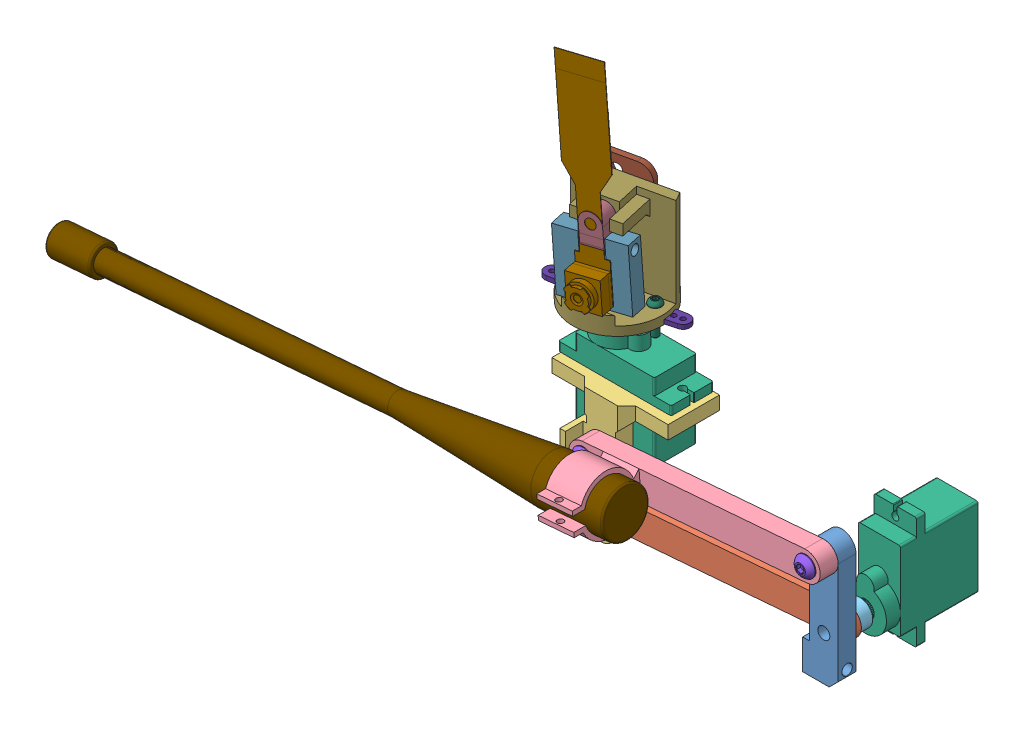
SolidWorks assembly 4barlift, configuration Default. Lengths in mm.
Overall size (209.39 119.55 61.9).
25 component instances, 18 part files, 60 mates.
Components (placement in the parent):
- UprightLinkage-3: UprightLinkage [Default] at (10.2426 1.5539 4.1287) size (10.06 32.9 5.08)
- LongLinkage_servointerface-3: LongLinkage_servointerface [Default] at (543.0293 904.0345 -372.7762) x (-0.080787 0.996731 0) z (0 0 1) size (8.13 71.63 5.08)
- TopLinkage-1: TopLinkage [Default] at (-53.0498 -3.5761 4.1287) size (33.02 35.81 22.23)
- LongLinkage-4: LongLinkage [Default] at (543.0293 923.0845 -362.6162) x (-0.080787 0.996731 0) z (0 0 1) size (15.87 71.63 24.1)
- servo horn 1 v2.step-1: servo horn 1 v2.step [Default] at (10.2426 1.5539 1.4047) x (0.080787 -0.996731 0) z (-0.996731 -0.080787 0) size (7.2 3.7 21.2)
- Towerpro Micro Servo 9g (1)-1: Towerpro Micro Servo 9g (1) [Varsayılan] at (10.2426 6.8039 -28.5953) x (-1 0 0) z (0 1 0) size (12 30 32)
- Towerpro Micro Servo 9g (1)-2: Towerpro Micro Servo 9g (1) [Varsayılan] at (-54.2298 13.1739 -1.8713) x (0 0 -1) z (1 0 0) size (12 30 32)
- 91028A411_JIS Hex Nut-1: 91028A411_JIS Hex Nut [91028A411] at (-53.0498 -3.5761 7.3607) x (0.882673 -0.469988 0) z (-0.469988 -0.882673 0) size (5.5 2.81 6.35)
- 91028A411_JIS Hex Nut-2: 91028A411_JIS Hex Nut [91028A411] at (10.2426 20.6039 5.9767) x (0.990104 -0.140335 0) z (0.140335 0.990104 0) size (5.5 2.81 6.35)
- 94500A223_316 Stainless Steel Button Head Hex Drive Screws-1: 94500A223_316 Stainless Steel Button Head Hex Drive Screws [94500A223] at (-53.0498 -3.5761 -2.6013) x (-0.923728 -0.383049 0) z (0 0 -1) size (5.7 5.7 11.96)
- 94500A223_316 Stainless Steel Button Head Hex Drive Screws-2: 94500A223_316 Stainless Steel Button Head Hex Drive Screws [94500A223] at (-53.0498 15.4739 15.9387) x (0.957545 0.288284 0) z (0 0 1) size (5.7 5.7 11.96)
- 94500A223_316 Stainless Steel Button Head Hex Drive Screws-3: 94500A223_316 Stainless Steel Button Head Hex Drive Screws [94500A223] at (10.2426 20.6039 15.9387) size (5.7 5.7 11.96)
- 91028A411_JIS Hex Nut-3: 91028A411_JIS Hex Nut [91028A411] at (-53.0498 15.4739 5.9767) x (-0.296491 0.955036 0) z (-0.955036 -0.296491 0) size (5.5 2.81 6.35)
- B006604.step-1: B006604.step [Default] at (-56.3424 53.482 7.8836) x (0.973205 0.071085 -0.218674) z (0.071693 -0.997413 -0.005162) size (12 6.7 59)
- hdmi_to_csi.step-1: hdmi_to_csi.step [Default] at (-63.9638 60.2486 -7.5722) x (-0.000051 -1 0.000012) z (0.219229 0 0.975673) size (29.21 18.09 5.45)
  - WURTH_685119136923.step-1: WURTH_685119136923.step [Default] at (-0.2673 -2.9788 -1.55) x (0 -1 0) z (0 0 -1) size (7.94 11.25 5.45)
    - COMPOUND.step-1: COMPOUND.step [Default] at origin size (7.94 11.25 5.45)
  - hdmi_to_csi PCB.step-1: hdmi_to_csi PCB.step [Default] at origin size (29.21 17.14 1.6)
- Gimbal_base-1: Gimbal_base [Default] at (-59.4798 43.1039 -1.8713) x (-0.975673 0 0.219229) z (-0.219229 0 -0.975673) size (25.4 27.94 25.4)
- Gimbal_middle-1: Gimbal_middle [Default] at (-57.2524 67.8469 8.0415) x (-0.973205 -0.071085 0.218674) z (-0.219229 0 -0.975673) size (5.84 10.56 5.08)
- Gimbal_top-1: Gimbal_top [Default] at (-58.3123 58.4802 5.7224) x (0.973205 0.071085 -0.218674) z (0.218475 0.010654 0.975784) size (18.29 17.06 4.57)
- 91239A705_Button Head Hex Drive Screw(4)-1: 91239A705_Button Head Hex Drive Screw(4) [91239A705] at (-50.6987 42.2939 -3.8444) x (-0.874255 0 -0.485467) z (0 1 0) size (3.5 3.5 9.37)
- 90592A004_Steel Hex Nut-1: 90592A004_Steel Hex Nut [90592A004] at (-50.6987 42.3739 -3.8444) x (0.954572 0 0.297979) z (0.297979 0 -0.954572) size (4 1.91 4.62)
- servo horn 3 v1.step-1: servo horn 3 v1.step [Default] at (-59.4798 43.1739 -1.8713) x (-0.219229 0 -0.975673) z (0.975673 0 -0.219229) size (17.2 3.7 35.2)
- Baofeng_antenna-1: Baofeng_antenna [Default] at (-31.7835 17.1976 23.4929) x (0 0 -1) z (-0.080787 0.996731 0) size (15.91 161.29 14.9)
Mates (geometry in assembly coordinates):
- Parallel1: parallel: plane of assembly through (0 0 0) normal (1 0 0); line of UprightLinkage-3 through (14.3066 -0.3492 4.1287) axis (0 1 0)
- Concentric7: concentric aligned: circle of UprightLinkage-1; circle of LongLinkage-2
- Coincident12: coincident anti-aligned: plane of UprightLinkage-3 through (10.2426 20.6039 9.2087) normal (0 0 1); plane of LongLinkage-2 through (-71.8994 143.2563 18.6451) normal (0 0 -1)
- Concentric8: concentric anti-aligned: circle of UprightLinkage-3; cylinder of LongLinkage_servointerface-3 through (10.2426 1.5539 4.1287) axis (0 0 -1) radius 4.064
- Coincident13: coincident anti-aligned: plane of UprightLinkage-3 through (10.2426 1.5539 4.1287) normal (0 0 -1); plane of LongLinkage_servointerface-3 through (-53.0498 -3.5761 4.1287) normal (0 0 1)
- Concentric9: concentric aligned: circle of LongLinkage-2; circle of TopLinkage-1
- Concentric10: concentric aligned: circle of LongLinkage-3; circle of TopLinkage-1
- Coincident14: coincident anti-aligned: plane of LongLinkage-2 through (-71.8994 143.2563 18.6451) normal (0 0 -1); plane of TopLinkage-1 through (-53.0498 -3.5761 9.2087) normal (0 0 1)
- Concentric13: concentric anti-aligned: cylinder of UprightLinkage-3 through (10.2426 20.6039 9.2087) axis (0 0 -1) radius 1.7; circle of LongLinkage-4
- Coincident23: coincident anti-aligned: plane of UprightLinkage-3 through (10.2426 1.5539 9.2087) normal (0 0 1); plane of LongLinkage-4 through (-53.0498 15.4739 9.2087) normal (0 0 -1)
- Coincident26: coincident anti-aligned: plane of TopLinkage-1 through (-53.0498 -3.5761 9.2087) normal (0 0 1); plane of LongLinkage-4 through (-53.0498 15.4739 9.2087) normal (0 0 -1)
- Parallel2: parallel anti-aligned: plane of LongLinkage_servointerface-3 through (-53.3781 0.4746 4.1287) normal (-0.080787 0.996731 0); plane of servo horn 1 v2.step-1 through (10.2426 1.5539 1.4047) normal (0.080787 -0.996731 0)
- Concentric15: concentric anti-aligned: circle of 91028A411_JIS Hex Nut-1; cylinder of TopLinkage-1 through (-53.0498 -3.5761 9.2087) axis (0 0 -1) radius 1.7
- Concentric20: concentric anti-aligned: cylinder of LongLinkage_servointerface-3 through (10.2426 1.5539 2.6047) axis (0 0 -1) radius 5.08; cylinder of servo horn 1 v2.step-1 through (10.2426 1.5539 1.4047) axis (0 0 1) radius 2.5
- Coincident34: coincident anti-aligned: plane of LongLinkage_servointerface-3 through (-6.0702 0.2317 2.6047) normal (0 0 -1); plane of servo horn 1 v2.step-1 through (3.2655 0.9883 2.6047) normal (0 0 1)
- Concentric21: concentric aligned: cylinder of UprightLinkage-3 through (10.2426 20.6039 9.2087) axis (0 0 -1) radius 1.7; circle of 91028A411_JIS Hex Nut-2
- Coincident36: coincident anti-aligned: plane of LongLinkage_servointerface-3 through (-53.0498 -3.5761 -0.9513) normal (0 0 -1); plane of 94500A223_316 Stainless Steel Button Head Hex Drive Screws-1 through (-49.3162 -5.1132 -0.9513) normal (0 0 1)
- Concentric23: concentric aligned: cylinder of LongLinkage_servointerface-3 through (-53.0498 -3.5761 4.1287) axis (0 0 -1) radius 1.7; circle of 94500A223_316 Stainless Steel Button Head Hex Drive Screws-1
- Coincident37: coincident anti-aligned: plane of LongLinkage-4 through (-53.0498 15.4739 14.2887) normal (0 0 1); plane of 94500A223_316 Stainless Steel Button Head Hex Drive Screws-3 through (7.3826 17.7539 14.2887) normal (0 0 -1)
- Concentric24: concentric anti-aligned: cylinder of LongLinkage-4 through (10.2426 20.6039 14.2887) axis (0 0 -1) radius 1.905; circle of 94500A223_316 Stainless Steel Button Head Hex Drive Screws-3
- Coincident38: coincident anti-aligned: plane of LongLinkage-4 through (-53.0498 15.4739 14.2887) normal (0 0 1); plane of 94500A223_316 Stainless Steel Button Head Hex Drive Screws-2 through (-54.9668 11.9204 14.2887) normal (0 0 -1)
- Concentric25: concentric anti-aligned: cylinder of LongLinkage-4 through (-53.0498 15.4739 14.2887) axis (0 0 -1) radius 1.905; circle of 94500A223_316 Stainless Steel Button Head Hex Drive Screws-2
- Concentric28: concentric anti-aligned: cylinder of TopLinkage-1 through (-53.0498 15.4739 9.2087) axis (0 0 -1) radius 1.7; circle of LongLinkage-4
- Concentric30: concentric aligned: cylinder of servo horn 1 v2.step-1 through (10.2426 1.5539 1.4047) axis (0 0 1) radius 2.5; circle of Towerpro Micro Servo 9g (1)-1
- Coincident42: coincident anti-aligned: plane of servo horn 1 v2.step-1 through (10.2426 1.5539 1.4047) normal (0 0 -1); plane of Towerpro Micro Servo 9g (1)-1 through (10.2426 1.5539 1.4047) normal (0 0 1)
- Concentric31: concentric aligned: circle of 91028A411_JIS Hex Nut-3; circle of 94500A223_316 Stainless Steel Button Head Hex Drive Screws-2
- Parallel8: parallel aligned: line of TopLinkage-1 through (-53.0498 -10.3833 4.1287) axis (0 1 0); line of Towerpro Micro Servo 9g (1)-2 through (-59.4798 35.1739 -1.8713) axis (0 1 0)
- Parallel7: parallel aligned: plane of TopLinkage-1 through (-53.0498 -3.5761 4.1287) normal (0 0 -1); plane of Towerpro Micro Servo 9g (1)-2 through (-64.9798 14.1739 -7.8713) normal (0 0 -1)
- Coincident43: coincident anti-aligned: plane of UprightLinkage-3 through (10.2426 1.5539 7.1767) normal (0 0 -1); plane of 91028A411_JIS Hex Nut-2 through (7.2971 19.4178 7.1767) normal (0 0 1)
- Concentric33: concentric aligned: circle of Towerpro Micro Servo 9g (1)-2; cylinder of servo horn 3 v1.step-1 through (-59.4798 43.1739 -1.8713) axis (0 1 0) radius 2.5
- Coincident49: coincident anti-aligned: plane of Towerpro Micro Servo 9g (1)-2 through (-59.4798 43.1739 -1.8713) normal (0 1 0); plane of servo horn 3 v1.step-1 through (-59.4798 43.1739 -1.8713) normal (0 -1 0)
- Concentric34: concentric anti-aligned: cylinder of servo horn 3 v1.step-1 through (-59.4798 43.1739 -1.8713) axis (0 1 0) radius 1.1; cylinder of Gimbal_base-1 through (-59.4798 45.6439 -1.8713) axis (0 -1 0) radius 12.7
- Concentric35: concentric aligned: cylinder of Gimbal_base-1 through (-59.7582 67.8469 -3.1104) axis (0.219229 0 0.975673) radius 1.397; cylinder of Gimbal_middle-1 through (-58.3661 67.8469 3.0851) axis (0.219229 0 0.975673) radius 1.397
- Coincident52: coincident anti-aligned: plane of servo horn 3 v1.step-1 through (-66.3095 44.3739 -0.3367) normal (0 1 0); plane of Gimbal_base-1 through (-58.0329 44.3739 4.5682) normal (0 -1 0)
- Distance1: distance = 0.762 mm anti-aligned: plane of Gimbal_middle-1 through (-58.3661 67.8469 3.0851) normal (-0.219229 0 -0.975673); plane of Gimbal_base-1 through (-58.5332 43.1039 2.3417) normal (0.219229 0 0.975673)
- Concentric37: concentric anti-aligned: cylinder of Gimbal_middle-1 through (-54.6127 62.9656 4.8451) axis (-0.973205 -0.071085 0.218674) radius 1.397; cylinder of Gimbal_top-1 through (-66.8443 62.0722 7.5935) axis (0.973205 0.071085 -0.218674) radius 1.397
- Distance2: distance = 0.1 mm anti-aligned: plane of Gimbal_top-1 through (-53.7782 59.6895 7.0367) normal (-0.973205 -0.071085 0.218674); plane of Gimbal_middle-1 through (-54.6127 62.9656 4.8451) normal (0.973205 0.071085 -0.218674)
- Coincident60: coincident anti-aligned: plane of B006604.step-1 through (-56.3861 53.4798 7.6884) normal (-0.218475 -0.010654 -0.975784); plane of Gimbal_top-1 through (-57.8129 58.5045 7.953) normal (0.218475 0.010654 0.975784)
- Coincident64: coincident anti-aligned: plane of hdmi_to_csi.step-1/hdmi_to_csi PCB.step-1 through (-63.613 60.2489 -6.0111) normal (0.219229 0 0.975673); plane of Gimbal_base-1 through (-71.977 71.0439 -4.1318) normal (-0.219229 0 -0.975673)
- Parallel18: parallel aligned: plane of B006604.step-1 through (-59.9093 57.4615 12.738) normal (-0.071693 0.997413 0.005162); plane of Gimbal_top-1 through (-48.7108 65.6766 5.8368) normal (-0.071693 0.997413 0.005162)
- Coincident66: coincident anti-aligned: plane of hdmi_to_csi.step-1/hdmi_to_csi PCB.step-1 through (-59.3179 45.6439 -8.6161) normal (0 -1 0); plane of Gimbal_base-1 through (-59.4798 45.6439 -1.8713) normal (0 1 0)
- Coincident69: coincident: point of hdmi_to_csi.step-1/hdmi_to_csi PCB.step-1; line of Gimbal_base-1 through (-71.977 71.0439 -4.1318) axis (0 -1 0)
- Distance3: distance = 1.27 mm: line of B006604.step-1 through (-51.9538 49.5914 6.9435) axis (-0.973205 -0.071085 0.218674); line of Gimbal_top-1 through (-65.2857 47.3612 9.7479) axis (0.973205 0.071085 -0.218674)
- Parallel26: parallel anti-aligned: plane of servo horn 3 v1.step-1 through (-59.4798 43.1739 -1.8713) normal (-0.219229 0 -0.975673); plane of Gimbal_base-1 through (-72.1634 71.0439 -1.2262) normal (0.219229 0 0.975673)
- Concentric38: concentric anti-aligned: circle of Gimbal_base-1; circle of 91239A705_Button Head Hex Drive Screw(4)-1
- Concentric39: concentric anti-aligned: circle of 91239A705_Button Head Hex Drive Screw(4)-1; circle of 90592A004_Steel Hex Nut-1
- Parallel27: parallel: line of Gimbal_base-1 through (-72.1634 45.6439 -1.2262) axis (0.975673 0 -0.219229); plane of 90592A004_Steel Hex Nut-1 through (-49.1337 41.5739 -2.1461) normal (0.219229 0 0.975673)
- Distance4: distance = 5.2964 mm aligned: plane of B006604.step-1 through (-59.2999 48.9835 12.6942) normal (-0.973205 -0.071085 0.218674); plane of Gimbal_top-1 through (-65.2857 47.3612 9.7479) normal (-0.973205 -0.071085 0.218674)
- Coincident75: coincident anti-aligned: plane of Gimbal_base-1 through (-59.4798 45.6439 -1.8713) normal (0 1 0); plane of 91239A705_Button Head Hex Drive Screw(4)-1 through (-51.1842 45.6439 -2.9701) normal (0 -1 0)
- Coincident76: coincident anti-aligned: plane of 90592A004_Steel Hex Nut-1 through (-52.952 43.1739 -3.3381) normal (0 1 0); plane of servo horn 3 v1.step-1 through (-52.6501 43.1739 -3.4059) normal (0 -1 0)
- Coincident77: coincident anti-aligned: plane of TopLinkage-1 through (-48.9858 28.1739 9.2087) normal (0 1 0); plane of Towerpro Micro Servo 9g (1)-2 through (-38.7298 28.1739 -7.3713) normal (0 -1 0)
- Coincident79: coincident anti-aligned: plane of TopLinkage-1 through (-53.0498 -3.5761 4.1287) normal (0 0 -1); plane of Towerpro Micro Servo 9g (1)-2 through (-64.9798 14.1739 4.1287) normal (0 0 1)
- Coincident80: coincident aligned: plane of TopLinkage-1 through (-64.4798 24.3639 4.1287) normal (1 0 0); plane of Towerpro Micro Servo 9g (1)-2 through (-64.4798 19.1739 2.1287) normal (1 0 0)
- Parallel28: parallel anti-aligned: plane of LongLinkage-4 through (543.0293 923.0845 -362.6162) normal (0 0 1); plane of Baofeng_antenna-1 through (-31.7835 17.1976 23.4929) normal (0 0 -1)
- Parallel29: parallel aligned: plane of LongLinkage-4 through (543.0293 923.0845 -362.6162) normal (-0.080787 0.996731 0); plane of Baofeng_antenna-1 through (-31.7835 17.1976 23.4929) normal (-0.080787 0.996731 0)
- Concentric40: concentric anti-aligned: cylinder of LongLinkage-4 through (-36.8469 16.7872 23.4929) axis (-0.996731 -0.080787 0) radius 6.6675; cylinder of Baofeng_antenna-1 through (-52.0371 15.556 23.4929) axis (0.996731 0.080787 0) radius 6.6675
- Distance5: distance = 5.08 mm aligned: plane of Baofeng_antenna-1 through (-31.7835 17.1976 23.4929) normal (0.996731 0.080787 0); plane of LongLinkage-4 through (-36.8469 16.7872 23.4929) normal (0.996731 0.080787 0)
- Coincident86: coincident aligned: plane of TopLinkage-1 through (-53.0498 -3.5761 7.1767) normal (0 0 -1); circle of 91028A411_JIS Hex Nut-3
- Coincident87: coincident anti-aligned: plane of TopLinkage-1 through (-53.0498 -3.5761 6.1607) normal (0 0 1); plane of 91028A411_JIS Hex Nut-1 through (-54.7309 -0.8822 6.1607) normal (0 0 -1)
- Parallel30: parallel aligned: plane of UprightLinkage-3 through (14.3066 1.5539 9.2087) normal (1 0 0); plane of Towerpro Micro Servo 9g (1)-1 through (16.2426 -3.9461 -27.5953) normal (1 0 0)
